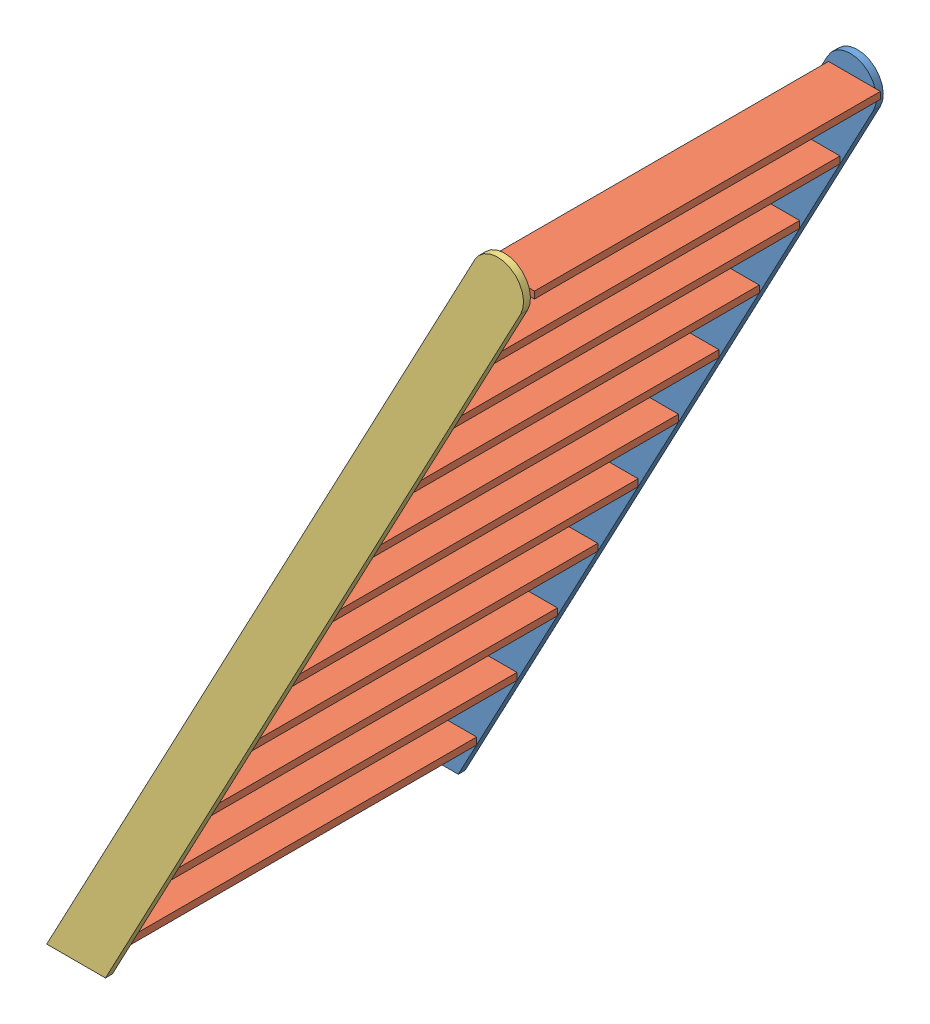
SolidWorks assembly Treppe, configuration Standard. Lengths in mm.
Overall size (1390.13 2371.85 1040).
13 component instances, 3 part files, 36 mates.
Components (placement in the parent):
- Treppengeländer-L-1: Treppengeländer-L [Standard] at (429.7662 -768.0145 2030.5107) size (1378.55 2371.85 20)
- Trittbrett-1: Trittbrett [Standard] at (-716.5983 -771.5592 2550.5107) x (0 0 -1) z (1 0 0) size (1000 20 150)
- Trittbrett-2: Trittbrett [Standard] at (-599.8717 -551.5592 2550.5107) x (0 0 -1) z (1 0 0) size (1000 20 150)
- Trittbrett-3: Trittbrett [Standard] at (-483.1452 -331.5592 2550.5107) x (0 0 -1) z (1 0 0) size (1000 20 150)
- Trittbrett-4: Trittbrett [Standard] at (-366.4186 -111.5592 2550.5107) x (0 0 -1) z (1 0 0) size (1000 20 150)
- Trittbrett-5: Trittbrett [Standard] at (-249.6921 108.4408 2550.5107) x (0 0 -1) z (1 0 0) size (1000 20 150)
- Trittbrett-6: Trittbrett [Standard] at (-132.9656 328.4408 2550.5107) x (0 0 -1) z (1 0 0) size (1000 20 150)
- Trittbrett-7: Trittbrett [Standard] at (-16.239 548.4408 2550.5107) x (0 0 -1) z (1 0 0) size (1000 20 150)
- Trittbrett-8: Trittbrett [Standard] at (100.4875 768.4408 2550.5107) x (0 0 -1) z (1 0 0) size (1000 20 150)
- Trittbrett-9: Trittbrett [Standard] at (217.214 988.4408 2550.5107) x (0 0 -1) z (1 0 0) size (1000 20 150)
- Trittbrett-10: Trittbrett [Standard] at (333.9406 1208.4408 2550.5107) x (0 0 -1) z (1 0 0) size (1000 20 150)
- Trittbrett-11: Trittbrett [Standard] at (450.6671 1428.4408 2550.5107) x (0 0 -1) z (1 0 0) size (1000 20 150)
- Treppengeländer-R-1: Treppengeländer-R [Standard] at (429.7662 -768.0145 3050.5107) size (1378.55 2371.85 20)
Mates (geometry in assembly coordinates):
- Deckungsgleich1: coincident anti-aligned: plane of Treppengeländer-L-1 through (439.092 1425.289 2050.5107) normal (0 0 1); plane of Trittbrett-1 through (-641.5983 -751.5592 2050.5107) normal (0 0 -1)
- Deckungsgleich2: coincident anti-aligned: plane of Treppengeländer-L-1 through (439.092 1425.289 2050.5107) normal (0 0 1); plane of Trittbrett-2 through (-524.8717 -531.5592 2050.5107) normal (0 0 -1)
- Deckungsgleich3: coincident anti-aligned: plane of Treppengeländer-L-1 through (439.092 1425.289 2050.5107) normal (0 0 1); plane of Trittbrett-3 through (-408.1452 -311.5592 2050.5107) normal (0 0 -1)
- Deckungsgleich4: coincident anti-aligned: plane of Treppengeländer-L-1 through (439.092 1425.289 2050.5107) normal (0 0 1); plane of Trittbrett-4 through (-291.4186 -91.5592 2050.5107) normal (0 0 -1)
- Deckungsgleich5: coincident anti-aligned: plane of Treppengeländer-L-1 through (439.092 1425.289 2050.5107) normal (0 0 1); plane of Trittbrett-5 through (-174.6921 128.4408 2050.5107) normal (0 0 -1)
- Deckungsgleich6: coincident anti-aligned: plane of Treppengeländer-L-1 through (439.092 1425.289 2050.5107) normal (0 0 1); plane of Trittbrett-6 through (-57.9656 348.4408 2050.5107) normal (0 0 -1)
- Deckungsgleich7: coincident anti-aligned: plane of Treppengeländer-L-1 through (439.092 1425.289 2050.5107) normal (0 0 1); plane of Trittbrett-7 through (58.761 568.4408 2050.5107) normal (0 0 -1)
- Deckungsgleich8: coincident anti-aligned: plane of Treppengeländer-L-1 through (439.092 1425.289 2050.5107) normal (0 0 1); plane of Trittbrett-8 through (175.4875 788.4408 2050.5107) normal (0 0 -1)
- Deckungsgleich10: coincident: plane of Treppengeländer-L-1 through (-694.6558 -871.5592 2050.5107) normal (0.883363 -0.46869 0); line of Trittbrett-8 through (175.4875 768.4408 3050.5107) axis (0 0 -1)
- Deckungsgleich11: coincident: plane of Treppengeländer-L-1 through (-694.6558 -871.5592 2050.5107) normal (0.883363 -0.46869 0); line of Trittbrett-7 through (58.761 548.4408 3050.5107) axis (0 0 -1)
- Deckungsgleich12: coincident: plane of Treppengeländer-L-1 through (-694.6558 -871.5592 2050.5107) normal (0.883363 -0.46869 0); line of Trittbrett-6 through (-57.9656 328.4408 3050.5107) axis (0 0 -1)
- Deckungsgleich13: coincident: plane of Treppengeländer-L-1 through (-694.6558 -871.5592 2050.5107) normal (0.883363 -0.46869 0); line of Trittbrett-5 through (-174.6921 108.4408 3050.5107) axis (0 0 -1)
- Deckungsgleich15: coincident: plane of Treppengeländer-L-1 through (-694.6558 -871.5592 2050.5107) normal (0.883363 -0.46869 0); line of Trittbrett-4 through (-291.4186 -111.5592 3050.5107) axis (0 0 -1)
- Deckungsgleich16: coincident: plane of Treppengeländer-L-1 through (-694.6558 -871.5592 2050.5107) normal (0.883363 -0.46869 0); line of Trittbrett-3 through (-408.1452 -331.5592 3050.5107) axis (0 0 -1)
- Deckungsgleich17: coincident: plane of Treppengeländer-L-1 through (-694.6558 -871.5592 2050.5107) normal (0.883363 -0.46869 0); line of Trittbrett-2 through (-524.8717 -551.5592 3050.5107) axis (0 0 -1)
- Deckungsgleich18: coincident: plane of Treppengeländer-L-1 through (-694.6558 -871.5592 2050.5107) normal (0.883363 -0.46869 0); line of Trittbrett-1 through (-641.5983 -771.5592 3050.5107) axis (0 0 -1)
- Abstand1: distance = 100 mm aligned: plane of Trittbrett-1 through (-716.5983 -771.5592 2550.5107) normal (0 -1 0); plane of Treppengeländer-L-1 through (-864.4615 -871.5592 2050.5107) normal (0 -1 0)
- Abstand2: distance = 200 mm anti-aligned: plane of Trittbrett-2 through (-599.8717 -551.5592 2550.5107) normal (0 -1 0); plane of Trittbrett-1 through (-716.5983 -751.5592 2550.5107) normal (0 1 0)
- Abstand3: distance = 200 mm anti-aligned: plane of Trittbrett-3 through (-483.1452 -331.5592 2550.5107) normal (0 -1 0); plane of Trittbrett-2 through (-599.8717 -531.5592 2550.5107) normal (0 1 0)
- Abstand4: distance = 200 mm anti-aligned: plane of Trittbrett-3 through (-483.1452 -311.5592 2550.5107) normal (0 1 0); plane of Trittbrett-4 through (-366.4186 -111.5592 2550.5107) normal (0 -1 0)
- Abstand5: distance = 200 mm anti-aligned: plane of Trittbrett-5 through (-249.6921 108.4408 2550.5107) normal (0 -1 0); plane of Trittbrett-4 through (-366.4186 -91.5592 2550.5107) normal (0 1 0)
- Abstand6: distance = 200 mm anti-aligned: plane of Trittbrett-6 through (-132.9656 328.4408 2550.5107) normal (0 -1 0); plane of Trittbrett-5 through (-249.6921 128.4408 2550.5107) normal (0 1 0)
- Abstand7: distance = 200 mm anti-aligned: plane of Trittbrett-7 through (-16.239 548.4408 2550.5107) normal (0 -1 0); plane of Trittbrett-6 through (-132.9656 348.4408 2550.5107) normal (0 1 0)
- Abstand8: distance = 200 mm anti-aligned: plane of Trittbrett-8 through (100.4875 768.4408 2550.5107) normal (0 -1 0); plane of Trittbrett-7 through (-16.239 568.4408 2550.5107) normal (0 1 0)
- Deckungsgleich27: coincident anti-aligned: plane of Treppengeländer-L-1 through (439.092 1425.289 2050.5107) normal (0 0 1); plane of Trittbrett-9 through (292.214 1008.4408 2050.5107) normal (0 0 -1)
- Deckungsgleich28: coincident anti-aligned: plane of Treppengeländer-L-1 through (439.092 1425.289 2050.5107) normal (0 0 1); plane of Trittbrett-10 through (408.9406 1228.4408 2050.5107) normal (0 0 -1)
- Deckungsgleich29: coincident: plane of Treppengeländer-L-1 through (-694.6558 -871.5592 2050.5107) normal (0.883363 -0.46869 0); line of Trittbrett-9 through (292.214 988.4408 3050.5107) axis (0 0 -1)
- Deckungsgleich30: coincident: plane of Treppengeländer-L-1 through (-694.6558 -871.5592 2050.5107) normal (0.883363 -0.46869 0); line of Trittbrett-10 through (408.9406 1208.4408 3050.5107) axis (0 0 -1)
- Abstand9: distance = 200 mm anti-aligned: plane of Trittbrett-8 through (100.4875 788.4408 2550.5107) normal (0 1 0); plane of Trittbrett-9 through (217.214 988.4408 2550.5107) normal (0 -1 0)
- Abstand10: distance = 200 mm anti-aligned: plane of Trittbrett-10 through (333.9406 1208.4408 2550.5107) normal (0 -1 0); plane of Trittbrett-9 through (217.214 1008.4408 2550.5107) normal (0 1 0)
- Deckungsgleich33: coincident anti-aligned: plane of Treppengeländer-L-1 through (439.092 1425.289 2050.5107) normal (0 0 1); plane of Trittbrett-11 through (525.6671 1448.4408 2050.5107) normal (0 0 -1)
- Deckungsgleich34: coincident: plane of Treppengeländer-L-1 through (-694.6558 -871.5592 2050.5107) normal (0.883363 -0.46869 0); line of Trittbrett-11 through (525.6671 1428.4408 3050.5107) axis (0 0 -1)
- Abstand11: distance = 200 mm anti-aligned: plane of Trittbrett-10 through (333.9406 1228.4408 2550.5107) normal (0 1 0); plane of Trittbrett-11 through (450.6671 1428.4408 2550.5107) normal (0 -1 0)
- Deckungsgleich36: coincident aligned: plane of Treppengeländer-L-1 through (-694.6558 -871.5592 2050.5107) normal (0.883363 -0.46869 0); plane of Treppengeländer-R-1 through (-694.6558 -871.5592 3070.5107) normal (0.883363 -0.46869 0)
- Deckungsgleich37: coincident aligned: plane of Treppengeländer-L-1 through (-864.4615 -871.5592 2050.5107) normal (0 -1 0); plane of Treppengeländer-R-1 through (-864.4615 -871.5592 3070.5107) normal (0 -1 0)
- Deckungsgleich38: coincident anti-aligned: plane of Trittbrett-1 through (-641.5983 -751.5592 3050.5107) normal (0 0 1); plane of Treppengeländer-R-1 through (439.092 1425.289 3050.5107) normal (0 0 -1)
